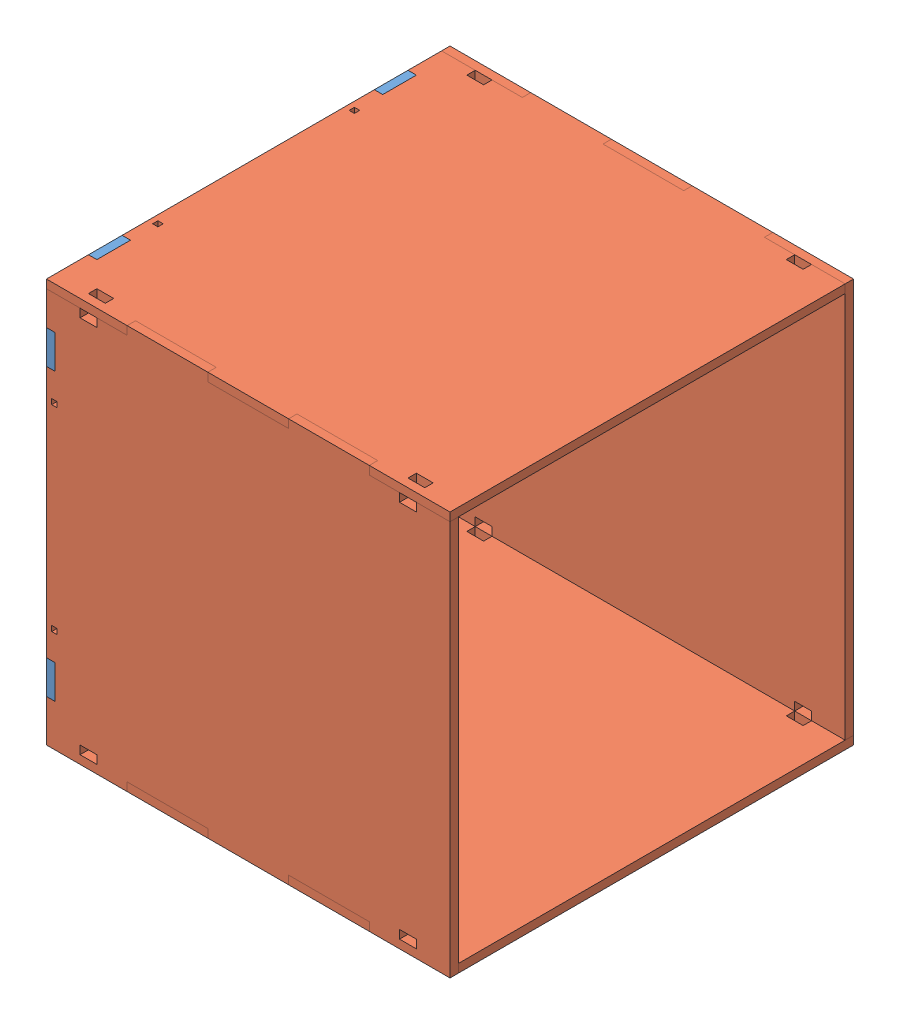
SolidWorks assembly plywood_cube, configuration Default. Lengths in mm.
Overall size (304.8 304.8 304.8).
8 component instances, 2 part files, 21 mates.
Components (placement in the parent):
- plywood_cube_corner_piece-1: plywood_cube_corner_piece [Default] at (-458.9877 -124.12 -305.2209) x (0 1 0) z (-1 0 0) size (69.85 69.85 6.35)
- plywood_cube_piece-1: plywood_cube_piece [Default] at (-398.5048 -140.6241 -95.7748) x (1 0 0) z (0 -1 0) size (304.8 304.8 6.35)
- plywood_cube_piece-5: plywood_cube_piece [Default] at (-398.5048 -108.7702 -356.0209) x (1 0 0) z (0 0 -1) size (304.8 304.8 6.35)
- plywood_cube_piece-6: plywood_cube_piece [Default] at (-398.5048 119.622 -63.9209) size (304.8 304.8 6.35)
- plywood_cube_piece-7: plywood_cube_piece [Default] at (-398.5048 151.4759 -324.167) x (1 0 0) z (0 1 0) size (304.8 304.8 6.35)
- plywood_cube_corner_piece-5: plywood_cube_corner_piece [Default] at (-465.3377 100.6759 -80.425) x (0 0 -1) z (1 0 0) size (69.85 69.85 6.35)
- plywood_cube_corner_piece-6: plywood_cube_corner_piece [Default] at (-465.3377 -124.12 -114.7209) x (0 1 0) z (1 0 0) size (69.85 69.85 6.35)
- plywood_cube_corner_piece-7: plywood_cube_corner_piece [Default] at (-458.9877 100.6759 -339.5168) x (0 0 1) z (-1 0 0) size (69.85 69.85 6.35)
Mates (geometry in assembly coordinates):
- Coincident13: coincident aligned: plane of plywood_cube_piece-1 through (-160.5377 -146.9741 -57.5709) normal (1 0 0); plane of plywood_cube_piece-6 through (-160.5377 157.8259 -57.5709) normal (1 0 0)
- Coincident14: coincident aligned: plane of plywood_cube_piece-5 through (-160.5377 -146.9741 -362.3709) normal (1 0 0); plane of plywood_cube_piece-6 through (-160.5377 157.8259 -57.5709) normal (1 0 0)
- Coincident15: coincident aligned: plane of plywood_cube_piece-5 through (-160.5377 -146.9741 -362.3709) normal (1 0 0); plane of plywood_cube_piece-7 through (-160.5377 157.8259 -362.3709) normal (1 0 0)
- Coincident16: coincident anti-aligned: plane of plywood_cube_piece-5 through (-398.5048 151.4759 -356.0209) normal (0 1 0); plane of plywood_cube_piece-7 through (-398.5048 151.4759 -324.167) normal (0 -1 0)
- Coincident17: coincident aligned: plane of plywood_cube_piece-5 through (-398.5048 -108.7702 -362.3709) normal (0 0 -1); plane of plywood_cube_piece-7 through (-465.3377 157.8259 -362.3709) normal (0 0 -1)
- Coincident18: coincident anti-aligned: plane of plywood_cube_piece-6 through (-398.5048 119.622 -63.9209) normal (0 0 -1); plane of plywood_cube_piece-7 through (-398.5048 151.4759 -63.9209) normal (0 0 1)
- Coincident19: coincident aligned: plane of plywood_cube_piece-6 through (-465.3377 157.8259 -57.5709) normal (0 1 0); plane of plywood_cube_piece-7 through (-398.5048 157.8259 -324.167) normal (0 1 0)
- Coincident31: coincident anti-aligned: plane of plywood_cube_piece-1 through (-398.5048 -140.6241 -95.7748) normal (0 1 0); plane of plywood_cube_piece-5 through (-343.4177 -140.6241 -356.0209) normal (0 -1 0)
- Coincident32: coincident aligned: plane of plywood_cube_piece-1 through (-465.3377 -146.9741 -362.3709) normal (0 0 -1); plane of plywood_cube_piece-5 through (-398.5048 -108.7702 -362.3709) normal (0 0 -1)
- Coincident33: coincident anti-aligned: plane of plywood_cube_piece-6 through (-458.9877 119.622 -63.9209) normal (-1 0 0); plane of plywood_cube_corner_piece-7 through (-458.9877 100.6759 -339.5168) normal (1 0 0)
- Coincident34: coincident aligned: plane of plywood_cube_piece-5 through (-398.5048 -108.7702 -362.3709) normal (0 0 -1); plane of plywood_cube_corner_piece-7 through (-465.3377 126.0759 -362.3709) normal (0 0 -1)
- Coincident35: coincident anti-aligned: plane of plywood_cube_piece-7 through (-398.5048 151.4759 -324.167) normal (0 -1 0); plane of plywood_cube_corner_piece-7 through (-465.3377 151.4759 -330.6209) normal (0 1 0)
- Coincident36: coincident aligned: plane of plywood_cube_piece-6 through (-465.3377 157.8259 -57.5709) normal (-1 0 0); plane of plywood_cube_corner_piece-6 through (-465.3377 -124.12 -114.7209) normal (-1 0 0)
- Coincident37: coincident aligned: plane of plywood_cube_piece-1 through (-398.5048 -146.9741 -95.7748) normal (0 -1 0); plane of plywood_cube_corner_piece-6 through (-458.9877 -146.9741 -89.3209) normal (0 -1 0)
- Coincident38: coincident aligned: plane of plywood_cube_piece-6 through (-398.5048 119.622 -57.5709) normal (0 0 1); plane of plywood_cube_corner_piece-6 through (-458.9877 -115.2241 -57.5709) normal (0 0 1)
- Coincident43: coincident aligned: plane of plywood_cube_piece-6 through (-398.5048 119.622 -57.5709) normal (0 0 1); plane of plywood_cube_corner_piece-5 through (-458.9877 126.0759 -57.5709) normal (0 0 1)
- Coincident44: coincident aligned: plane of plywood_cube_piece-7 through (-398.5048 157.8259 -324.167) normal (0 1 0); plane of plywood_cube_corner_piece-5 through (-458.9877 157.8259 -89.3209) normal (0 1 0)
- Coincident45: coincident aligned: plane of plywood_cube_piece-6 through (-465.3377 157.8259 -57.5709) normal (-1 0 0); plane of plywood_cube_corner_piece-5 through (-465.3377 100.6759 -80.425) normal (-1 0 0)
- Coincident46: coincident aligned: plane of plywood_cube_corner_piece-1 through (-465.3377 -124.12 -305.2209) normal (-1 0 0); plane of plywood_cube_piece-5 through (-465.3377 -146.9741 -362.3709) normal (-1 0 0)
- Coincident47: coincident aligned: plane of plywood_cube_corner_piece-1 through (-465.3377 -146.9741 -330.6209) normal (0 -1 0); plane of plywood_cube_piece-1 through (-398.5048 -146.9741 -95.7748) normal (0 -1 0)
- Coincident48: coincident aligned: plane of plywood_cube_corner_piece-1 through (-465.3377 -115.2241 -362.3709) normal (0 0 -1); plane of plywood_cube_piece-5 through (-398.5048 -108.7702 -362.3709) normal (0 0 -1)
